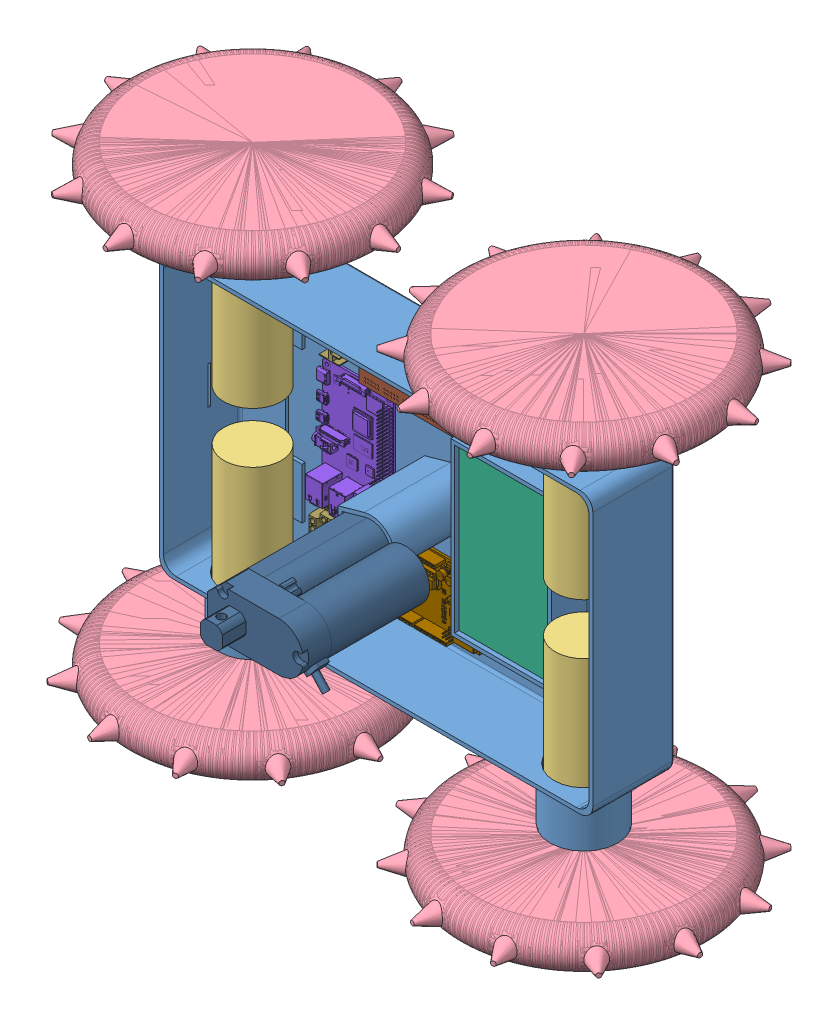
SolidWorks assembly Assem1, configuration Default. Lengths in mm.
Overall size (576.8 370 324.84).
34 component instances, 19 part files, 46 mates.
Components (placement in the parent):
- Bodyv2-1: Bodyv2 [Default] at (-16.1908 13.9668 -36.6938) size (345.21 296 72)
- Camera-2: Camera [Default] at (-172.0833 15.1294 -36.6938) x (0 0 -1) z (1 0 0) size (6.45 24 25)
- motor_wheel_sub_assemb-6: motor_wheel_sub_assemb [Default] at (51.3365 17.8539 -33.7411) x (0.859581 0 -0.511) z (0 -1 0) size (313.91 313.91 165)
  - motorV2-1: motorV2 [Default] at (39.3682 56.0325 23.8871) size (45 45 150)
  - WheelV2-2: WheelV2 [Default] at (39.3682 56.0325 173.8871) x (0.747256 0.664536 0) z (0 0 1) size (230 230 30)
  - key-1: key [Default] at (39.3682 59.2175 163.8871) x (0 0 -1) z (1 0 0) size (20 6 4)
- motor_wheel_sub_assemb-7: motor_wheel_sub_assemb [Default] at (-93.6313 17.8539 -49.5913) x (0.083274 0 0.996527) z (0 -1 0) size (313.91 313.91 165)
  - motorV2-1: motorV2 [Default] at (39.3682 56.0325 23.8871) size (45 45 150)
  - WheelV2-2: WheelV2 [Default] at (39.3682 56.0325 173.8871) x (0.747256 0.664536 0) z (0 0 1) size (230 230 30)
  - key-1: key [Default] at (39.3682 59.2175 163.8871) x (0 0 -1) z (1 0 0) size (20 6 4)
- motor_wheel_sub_assemb-8: motor_wheel_sub_assemb [Default] at (-126.1412 10.0797 -71.1729) x (-0.950693 0 0.310132) z (0 1 0) size (313.91 313.91 165)
  - motorV2-1: motorV2 [Default] at (39.3682 56.0325 23.8871) size (45 45 150)
  - WheelV2-2: WheelV2 [Default] at (39.3682 56.0325 173.8871) x (0.747256 0.664536 0) z (0 0 1) size (230 230 30)
  - key-1: key [Default] at (39.3682 59.2175 163.8871) x (0 0 -1) z (1 0 0) size (20 6 4)
- motor_wheel_sub_assemb-9: motor_wheel_sub_assemb [Default] at (107.5876 10.0797 62.5028) x (0.867079 0 -0.49817) z (0 1 0) size (313.91 313.91 165)
  - motorV2-1: motorV2 [Default] at (39.3682 56.0325 23.8871) size (45 45 150)
  - WheelV2-2: WheelV2 [Default] at (39.3682 56.0325 173.8871) x (0.747256 0.664536 0) z (0 0 1) size (230 230 30)
  - key-1: key [Default] at (39.3682 59.2175 163.8871) x (0 0 -1) z (1 0 0) size (20 6 4)
- batteryV2-2: batteryV2 [Default] at (49.8092 9.6063 -32.6938) x (0 1 0) z (0 0 1) size (126.79 72 25)
- actuator_stroke-2: actuator_stroke [Default] at (-12.5408 13.9668 22.3102) x (-1 0 0) z (0 -1 0) size (20.1 100 20.1)
- Raspberry Pi 4 Model B-3: Raspberry Pi 4 Model B [Default] at (-88.9739 12.9246 -31.8938) x (-0.001818 -0.999998 0) z (-0.999998 0.001818 0) size (88.99 19.9 58.4)
- arduino uno-2: arduino uno [Default] at (6.6097 -32.5972 -31.0438) x (0 1 0) z (1 0 0) size (53.34 15.25 74.93)
- LinearActuator-100mm-4: LinearActuator-100mm [Default] at (-31.9883 13.9668 125.7737) x (0 -1 0) z (0 0 -1) size (45.33 82.92 192.97)
- small_breadboard v1-2: small_breadboard v1 [Default] at (-33.6826 89.9638 -30.3438) x (0 1 0) z (0 0 1) size (54.39 82.89 9.7)
- L298N_DriverSLDPRT-1: L298N_DriverSLDPRT [Default] at (-51.3943 3.2802 -19.3989) x (0 -1 0) z (-1 0 0) size (43 28.02 43)
- L298N_DriverSLDPRT-2: L298N_DriverSLDPRT [Default] at (-47.5713 -152.2328 -19.3989) x (0 -1 0) z (-1 0 0) size (43 28.02 43)
- RelayBoardSLDPRT-1: RelayBoardSLDPRT [Default] at (48.3831 97.5995 -32.6938) x (1 0 0) z (0 -1 0) size (50.55 19.3 36.88)
- tool_assembly-2: tool_assembly [Default] at (-62.96 3.7324 -92.374) x (0 1 0) z (0.997093 0 -0.0762) size (66.91 39.49 93.69)
  - tool_casing-1: tool_casing [Default] at (25.653 23.4689 8.7727) size (36 33 80)
  - blade-4: blade [Default] at (10.653 -12.7711 28.3027) x (0.469779 0 -0.882784) z (0.882784 0 0.469779) size (46.3 2 53.46)
  - BO DC Motor-1: BO DC Motor [Default] at (10.653 5.9389 28.3027) size (22.5 37.42 69.3)
  - connector-2: connector [Default] at (23.153 23.4689 48.7727) x (0 -1 0) z (0 0 -1) size (6.5 45 6.5)
  - Part8^tool_assembly-1: Part8^tool_assembly [Default] at origin (virtual)
  - assembley component-1: assembley component [Default] at (-10.347 6.4689 88.7727) x (0 0 -1) z (1 0 0) size (80 20 3)
Mates (geometry in assembly coordinates):
- Width1: width aligned: plane of batteryV2-1 through (90.8092 77.3618 -7.6938) normal (0 1 0); plane of batteryV2-1 through (90.8092 -49.4282 -7.6938) normal (0 -1 0); plane of Bodyv2-1 through (-183.1908 -93.0332 27.3062) normal (0 1 0); plane of Bodyv2-1 through (150.8092 120.9668 27.3062) normal (0 -1 0)
- Coincident1: coincident anti-aligned: plane of Bodyv2-1 through (-16.1908 13.9668 -32.6938) normal (0 0 1); plane of batteryV2-1 through (54.8092 13.9668 -32.6938) normal (0 0 -1)
- Distance1: distance = 70 mm anti-aligned: plane of Bodyv2-1 through (150.8092 -93.0332 27.3062) normal (-1 0 0); plane of batteryV2-1 through (90.8092 -49.4282 -7.6938) normal (1 0 0)
- Coincident4: coincident anti-aligned: plane of Bodyv2-1 through (-16.1908 13.9668 -32.6938) normal (0 0 1); plane of Raspberry Pi 4 Model B-1 through (-91.8696 72.6846 -32.6938) normal (0 0 -1)
- Coincident5: coincident anti-aligned: plane of Bodyv2-1 through (-16.1908 13.9668 -32.6938) normal (0 0 1); plane of arduino uno-1 through (-127.5372 -64.1728 -32.6938) normal (0 0 -1)
- Coincident7: coincident: plane of Bodyv2-1 through (-16.1908 13.9668 -36.6938) normal (0 0 -1); plane of Camera-2 through (-172.0833 15.1294 -36.6938) normal (0 0 1)
- Concentric9: concentric aligned: circle of Bodyv2-1; circle of motor_wheel_sub_assemb-1/motorV2-1
- Coincident18: coincident anti-aligned: plane of Bodyv2-1 through (-183.1908 -93.0332 27.3062) normal (0 1 0); circle of motor_wheel_sub_assemb-1/motorV2-1
- Concentric10: concentric aligned: circle of Bodyv2-1; circle of motor_wheel_sub_assemb-2/motorV2-1
- Coincident19: coincident anti-aligned: plane of Bodyv2-1 through (-183.1908 -93.0332 27.3062) normal (0 1 0); plane of motor_wheel_sub_assemb-2/motorV2-1 through (156.8092 -84.0332 -18.6938) normal (0 -1 0)
- Concentric11: concentric anti-aligned: circle of Bodyv2-1; circle of motor_wheel_sub_assemb-4/motorV2-1
- Coincident20: coincident anti-aligned: plane of Bodyv2-1 through (150.8092 120.9668 27.3062) normal (0 -1 0); plane of motor_wheel_sub_assemb-4/motorV2-1 through (-189.1908 111.9668 -18.6938) normal (0 1 0)
- Concentric12: concentric anti-aligned: circle of Bodyv2-1; circle of motor_wheel_sub_assemb-5/motorV2-1
- Coincident21: coincident anti-aligned: plane of Bodyv2-1 through (150.8092 120.9668 27.3062) normal (0 -1 0); plane of motor_wheel_sub_assemb-5/motorV2-1 through (156.8092 111.9668 -18.6938) normal (0 1 0)
- Coincident23: coincident anti-aligned: plane of Bodyv2-1 through (-16.1908 13.9668 -32.6938) normal (0 0 1); plane of LinearActuator-100mm-1 through (15 12.9668 -32.6938) normal (0 0 -1)
- Parallel3: parallel anti-aligned: plane of LinearActuator-100mm-1 through (-19.4476 12.9668 125.7737) normal (0 -1 0)
- Concentric14: concentric aligned: circle of Bodyv2-1; circle of LinearActuator-100mm-1
- Parallel6: parallel anti-aligned: plane of LinearActuator-100mm-1 through (0 12.9668 43.8062) normal (0 0 -1); plane of actuator_stroke-1 through (0 12.9668 36.2213) normal (0 0 1)
- Concentric15: concentric anti-aligned: circle of Bodyv2-1; circle of actuator_stroke-1
- Coincident27: coincident aligned: plane of LinearActuator-100mm-1 through (-19.4476 12.9668 125.7737) normal (0 -1 0); plane of actuator_stroke-1 through (0 12.9668 36.2213) normal (0 -1 0)
- Coincident30: coincident anti-aligned: plane of Bodyv2-1 through (-146.1908 -131.0332 -5.6938) normal (0 1 0); plane of motor_wheel_sub_assemb-7/motorV2-1 through (-146.1908 -131.0332 -5.6938) normal (0 -1 0)
- Concentric20: concentric aligned: cylinder of motor_wheel_sub_assemb-9/motorV2-1 through (113.8092 158.9668 -5.6938) axis (0 -1 0) radius 22.5; circle of Bodyv2-1
- Concentric21: concentric anti-aligned: circle of motor_wheel_sub_assemb-7/motorV2-1; cylinder of Bodyv2-1 through (-146.1908 -96.0332 -5.6938) axis (0 1 0) radius 23.5
- Concentric22: concentric anti-aligned: cylinder of Bodyv2-1 through (-146.1908 -96.0332 -5.6938) axis (0 1 0) radius 23.5; cylinder of motor_wheel_sub_assemb-8/motorV2-1 through (-146.1908 158.9668 -5.6938) axis (0 -1 0) radius 22.5
- Coincident33: coincident anti-aligned: plane of Bodyv2-1 through (-146.1908 158.9668 -5.6938) normal (0 -1 0); plane of motor_wheel_sub_assemb-8/motorV2-1 through (-146.1908 158.9668 -5.6938) normal (0 1 0)
- Concentric23: concentric aligned: circle of Bodyv2-1; cylinder of motor_wheel_sub_assemb-6/motorV2-1 through (113.8092 -131.0332 -5.6938) axis (0 1 0) radius 22.5
- Coincident34: coincident anti-aligned: plane of Bodyv2-1 through (113.8092 -131.0332 -5.6938) normal (0 1 0); plane of motor_wheel_sub_assemb-6/motorV2-1 through (113.8092 -131.0332 -5.6938) normal (0 -1 0)
- Coincident35: coincident anti-aligned: plane of Bodyv2-1 through (113.8092 158.9668 -5.6938) normal (0 -1 0); plane of motor_wheel_sub_assemb-9/motorV2-1 through (113.8092 158.9668 -5.6938) normal (0 1 0)
- Coincident36: coincident anti-aligned: plane of Bodyv2-1 through (-16.1908 13.9668 -32.6938) normal (0 0 1); plane of batteryV2-2 through (49.8092 9.6063 -32.6938) normal (0 0 -1)
- Width2: width = 39.2445 mm anti-aligned: plane of Bodyv2-1 through (-183.1908 -93.0332 27.3062) normal (0 1 0); plane of Bodyv2-1 through (150.8092 120.9668 27.3062) normal (0 -1 0); plane of batteryV2-2 through (85.8092 -53.7887 -7.6938) normal (0 -1 0); plane of batteryV2-2 through (85.8092 73.0013 -7.6938) normal (0 1 0)
- Distance2: distance = 65 mm anti-aligned: plane of batteryV2-2 through (85.8092 -53.7887 -7.6938) normal (1 0 0); plane of Bodyv2-1 through (150.8092 -93.0332 27.3062) normal (-1 0 0)
- Coincident39: coincident anti-aligned: plane of Bodyv2-1 through (-16.1908 13.9668 -36.6938) normal (0 1 0); plane of LinearActuator-100mm-3 through (-18.9883 13.9668 125.7737) normal (0 -1 0)
- Distance3: distance = 162 mm anti-aligned: plane of LinearActuator-100mm-3 through (-21.1908 13.9668 119.7262) normal (-1 0 0); plane of Bodyv2-1 through (-183.1908 120.9668 27.3062) normal (1 0 0)
- Coincident40: coincident anti-aligned: plane of Bodyv2-1 through (-16.1908 13.9668 -32.6938) normal (0 0 1); plane of LinearActuator-100mm-3 through (15.4592 13.9668 -32.6938) normal (0 0 -1)
- Concentric24: concentric anti-aligned: cylinder of LinearActuator-100mm-3 through (0.4592 13.9668 43.8062) axis (0 0 -1) radius 10.05; cylinder of actuator_stroke-2 through (-12.5408 13.9668 -77.6898) axis (0 0 1) radius 10.05
- Coincident41: coincident: plane of Bodyv2-1 through (-16.1908 13.9668 -32.6938) normal (0 0 1); plane of arduino uno-2 through (6.6097 -32.5972 -32.6938) normal (0 0 -1)
- Coincident43: coincident: plane of Bodyv2-1 through (-16.1908 13.9668 -32.6938) normal (0 0 1); plane of Raspberry Pi 4 Model B-3 through (-88.9739 12.9246 -32.6938) normal (0 0 -1)
- Coincident45: coincident anti-aligned: plane of Bodyv2-1 through (-16.1908 13.9668 -36.6938) normal (0 1 0); plane of LinearActuator-100mm-4 through (-31.9883 13.9668 125.7737) normal (0 -1 0)
- Distance4: distance = 149 mm anti-aligned: plane of LinearActuator-100mm-4 through (-34.1908 13.9668 119.7262) normal (-1 0 0); plane of Bodyv2-1 through (-183.1908 120.9668 27.3062) normal (1 0 0)
- Coincident47: coincident anti-aligned: plane of Bodyv2-1 through (-16.1908 13.9668 -32.6938) normal (0 0 1); plane of LinearActuator-100mm-4 through (2.4592 13.9668 -32.6938) normal (0 0 -1)
- Coincident48: coincident: plane of Bodyv2-1 through (-16.1908 13.9668 -32.6938) normal (0 0 1); plane of L298N_DriverSLDPRT-1 through (-78.4051 114.1685 -32.6938) normal (0 0 -1)
- Coincident49: coincident: plane of Bodyv2-1 through (-16.1908 13.9668 -32.6938) normal (0 0 1); plane of L298N_DriverSLDPRT-2 through (-74.5821 -41.3444 -32.6938) normal (0 0 -1)
- Coincident50: coincident: plane of Bodyv2-1 through (-16.1908 13.9668 -32.6938) normal (0 0 1); plane of RelayBoardSLDPRT-1 through (48.3831 97.5995 -32.6938) normal (0 0 -1)
- Concentric25: concentric anti-aligned: cylinder of actuator_stroke-2 through (-12.5408 13.9668 -77.6898) axis (0 0 1) radius 10.05; cylinder of LinearActuator-100mm-4 through (-12.5408 13.9668 43.8062) axis (0 0 -1) radius 10.05
- Parallel9: parallel anti-aligned: plane of actuator_stroke-2 through (-12.5408 13.9668 22.3102) normal (0 -1 0)
- Concentric26: concentric anti-aligned: cylinder of actuator_stroke-2 through (-12.5408 24.0168 -72.6898) axis (0 -1 0) radius 3.25; cylinder of tool_assembly-2/connector-2 through (-12.5408 1.8854 -72.6898) axis (0 1 0) radius 3.25
